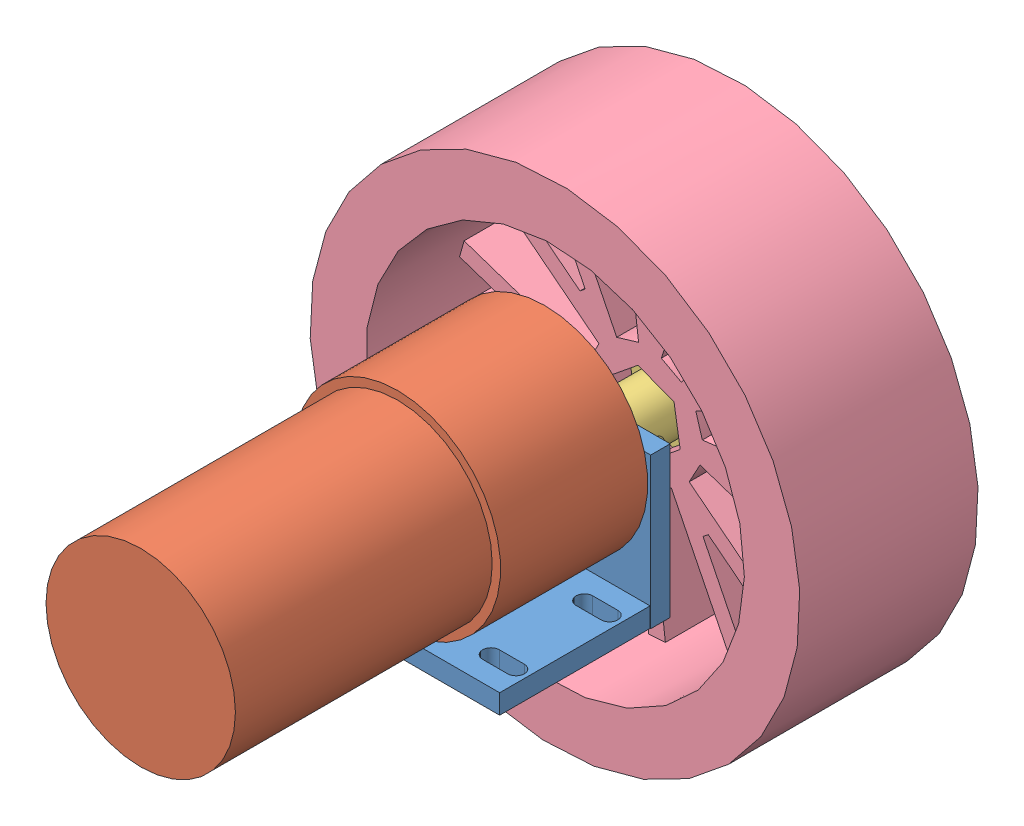
SolidWorks assembly 电机-轮子直连, configuration Default. Lengths in mm.
Overall size (123.81 123.81 106.36).
5 component instances, 4 part files, 7 mates.
Components (placement in the parent):
- DC_AssemFinal-1: DC_AssemFinal [默认] at (-4.4769 21.3488 36.3494) size (38.11 40.75 94.36)
  - DC_MountFinalProject-1: DC_MountFinalProject [默认] at (16.5399 8.7711 35.5816) size (38.11 27 30.5)
  - DC_FinalProject-1: DC_FinalProject [默认] at (16.626 31.0211 94.5976) x (-1 0 0) z (0 -1 0) size (37 94.36 37)
- DShaftAdaptor_FinalProject-1: DShaftAdaptor_FinalProject [默认] at (12.1491 45.2578 48.5889) x (0.355741 0.934584 0) z (-0.934584 0.355741 0) size (12 18.01 13.86)
- Wheel-1: Wheel [Default] at (12.1491 45.2578 56.5889) x (-0.775373 -0.631503 0) z (0 0 -1) size (88 88 32)
Mates (geometry in assembly coordinates):
- 同心1: concentric aligned: cylinder of DC_AssemFinal-1/DC_FinalProject-1 through (12.1491 45.2578 36.5889) axis (0 0 1) radius 3; cylinder of DShaftAdaptor_FinalProject-1 through (12.1491 45.2578 36.5889) axis (0 0 1) radius 3
- 同心2: concentric anti-aligned: cylinder of DShaftAdaptor_FinalProject-1 through (12.1491 45.2578 36.5889) axis (0 0 1) radius 3; cylinder of Wheel-1 through (12.1491 45.2578 40.5889) axis (0 0 -1) radius 3
- 重合1: coincident anti-aligned: plane of DShaftAdaptor_FinalProject-1 through (12.1491 45.2578 30.5889) normal (0 0 -1); plane of Wheel-1 through (12.1491 45.2578 30.5889) normal (0 0 1)
- 重合2: coincident anti-aligned: plane of DShaftAdaptor_FinalProject-1 through (13.2522 38.418 30.5889) normal (-0.355741 -0.934584 0); plane of Wheel-1 through (6.7772 40.8826 30.5889) normal (0.355741 0.934584 0)
- 重合3: coincident anti-aligned: plane of DShaftAdaptor_FinalProject-1 through (18.6241 42.7932 30.5889) normal (0.631503 -0.775373 0); plane of Wheel-1 through (13.2522 38.418 30.5889) normal (-0.631503 0.775373 0)
- 重合4: coincident anti-aligned: plane of DShaftAdaptor_FinalProject-1 through (17.521 49.633 30.5889) normal (0.987245 0.159211 0); plane of Wheel-1 through (18.6241 42.7932 30.5889) normal (-0.987245 -0.159211 0)
- 重合5: coincident anti-aligned: plane of DC_AssemFinal-1/DC_FinalProject-1 through (12.1491 45.2578 36.5889) normal (0 0 -1); plane of DShaftAdaptor_FinalProject-1 through (12.1491 45.2578 36.5889) normal (0 0 1)
